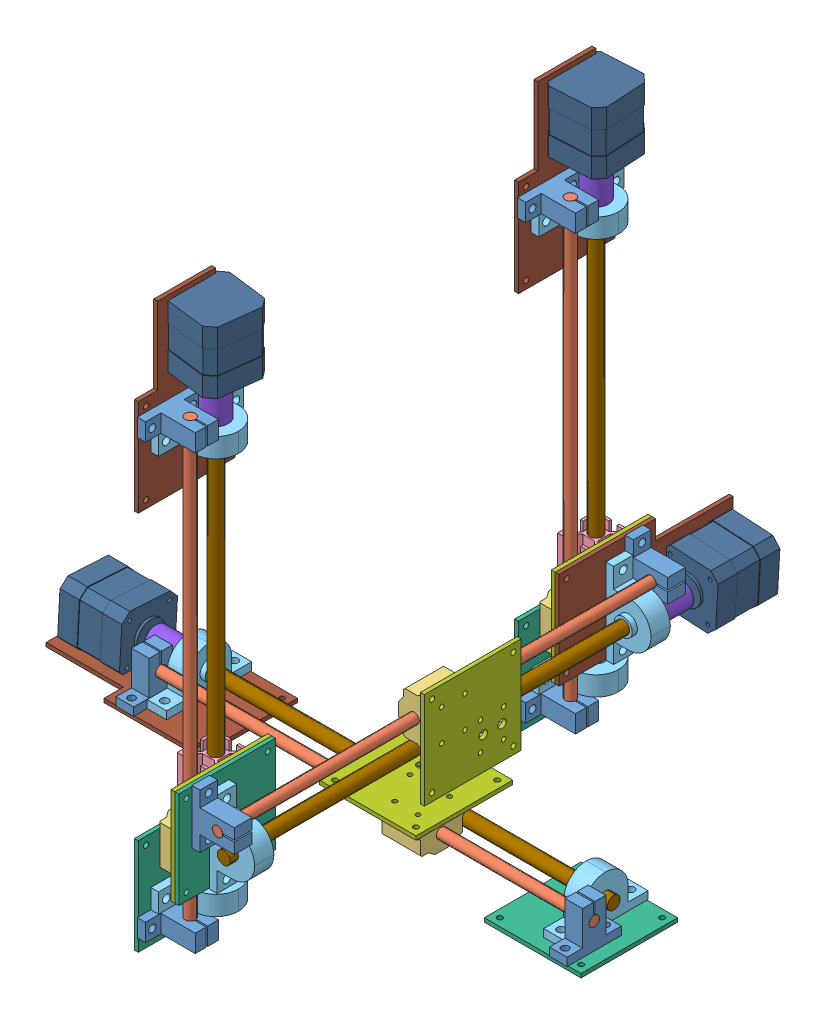
SolidWorks assembly PrinterAssembly, configuration Default. Lengths in mm.
Overall size (430 438.36 430).
60 component instances, 12 part files, 7 mates.
Components (placement in the parent):
- printer-1: printer [Default] at (379.3721 364.6591 311.6368) x (0 -1 0) z (0 0 1) size (442 48.34 82.75) (flexible)
  - M8_ Mil_Tutucu-4: M8_ Mil_Tutucu [Default] at (5.5091 -3.3233 99.5698) size (13.7 33 42)
  - M8_ Mil_Tutucu-5: M8_ Mil_Tutucu [Default] at (341.8091 -3.3233 99.5698) size (13.7 33 42)
  - M8_300_Mil-3: M8_300_Mil [Default] at (348.6591 16.7219 99.5698) x (0 0.969737 -0.244154) z (-1 0 0) size (8 8 350)
  - M8_Linear_Rulman-2: M8_Linear_Rulman [Default] at (296.9869 26.0544 99.5698) x (0 0 -1) z (-1 0 0) size (34.5 22.33 30)
  - Part4^printer-1: Part4^printer [Default] at origin (virtual)
  - 8mm_nut_profile-1: 8mm_nut_profile [Default] at (266.9869 14.1767 77.0698) x (0 0 1) z (-1 0 0) size (30 30 30)
  - UCP_10mm-1: UCP_10mm [Default] at (327.4591 -3.3233 77.0698) x (0 0 1) z (-1 0 0) size (66 35 19)
  - UCP_10mm-2: UCP_10mm [Default] at (19.8591 -3.3233 77.0698) x (0 0 -1) z (1 0 0) size (66 35 19)
  - Connection_Plate_Side-1: Connection_Plate_Side [Default] at (321.1591 -6.3233 82.3198) size (75 3 75)
  - Connection_Plate_Middle-1: Connection_Plate_Middle [Default] at (266.9869 29.1767 89.3198) size (75 3 75)
  - Kaplin_5-10mm-1: Kaplin_5-10mm [Default] at (11.3591 14.1767 77.0698) x (0 0.873711 0.486446) z (0 -0.486446 0.873711) size (19 25 19)
  - M10_Vidali_Mil-1: M10_Vidali_Mil [Default] at (1.3591 14.1767 77.0698) x (0 -0.999482 -0.03217) z (0 -0.03217 0.999482) size (10 340 10)
  - Nema17_stepper-1: Nema17_stepper [Default] at (-67.6409 14.1767 77.0698) x (0 -0.992266 -0.124131) z (0 -0.124131 0.992266) size (43.3 72 43.3)
  - Connection_Plate_Side_Stepper-1: Connection_Plate_Side_Stepper [Default] at (26.1591 -6.3233 82.3198) x (0 0 -1) z (1 0 0) size (75 3 135)
- printer-2: printer [Default] at (417.8721 15.3524 79.7975) x (0 0 1) z (0 1 0) size (442 45.72 82.75) (flexible)
  - M8_ Mil_Tutucu-4: M8_ Mil_Tutucu [Default] at (5.5091 -3.3233 99.5698) size (13.7 33 42)
  - M8_ Mil_Tutucu-5: M8_ Mil_Tutucu [Default] at (341.8091 -3.3233 99.5698) size (13.7 33 42)
  - M8_300_Mil-3: M8_300_Mil [Default] at (348.6591 16.7219 99.5698) x (0 0.969737 -0.244154) z (-1 0 0) size (8 8 350)
  - M8_Linear_Rulman-2: M8_Linear_Rulman [Default] at (196.1347 26.0544 99.5698) x (0 0 -1) z (-1 0 0) size (34.5 22.33 30)
  - Part4^printer-1: Part4^printer [Default] at origin (virtual)
  - 8mm_nut_profile-1: 8mm_nut_profile [Default] at (166.1347 14.1767 77.0698) x (0 0 1) z (-1 0 0) size (30 30 30)
  - UCP_10mm-1: UCP_10mm [Default] at (327.4591 -3.3233 77.0698) x (0 0 1) z (-1 0 0) size (66 35 19)
  - UCP_10mm-2: UCP_10mm [Default] at (19.8591 -3.3233 77.0698) x (0 0 -1) z (1 0 0) size (66 35 19)
  - Connection_Plate_Side-1: Connection_Plate_Side [Default] at (321.1591 -6.3233 82.3198) size (75 3 75)
  - Connection_Plate_Middle-1: Connection_Plate_Middle [Default] at (166.1347 29.1767 89.3198) size (75 3 75)
  - Kaplin_5-10mm-1: Kaplin_5-10mm [Default] at (11.3591 14.1767 77.0698) x (0 0.873711 0.486446) z (0 -0.486446 0.873711) size (19 25 19)
  - M10_Vidali_Mil-1: M10_Vidali_Mil [Default] at (1.3591 14.1767 77.0698) x (0 -0.999482 -0.03217) z (0 -0.03217 0.999482) size (10 340 10)
  - Nema17_stepper-1: Nema17_stepper [Default] at (-67.6409 14.1767 77.0698) x (0 -0.998341 0.05758) z (0 0.05758 0.998341) size (43.3 72 43.3)
  - Connection_Plate_Side_Stepper-1: Connection_Plate_Side_Stepper [Default] at (26.1591 -6.3233 82.3198) x (0 0 -1) z (1 0 0) size (75 3 135)
- printer-3: printer [Default] at (379.3721 364.6591 16.6368) x (0 -1 0) z (0 0 1) size (442 45.72 82.75) (flexible)
  - M8_ Mil_Tutucu-4: M8_ Mil_Tutucu [Default] at (5.5091 -3.3233 99.5698) size (13.7 33 42)
  - M8_ Mil_Tutucu-5: M8_ Mil_Tutucu [Default] at (341.8091 -3.3233 99.5698) size (13.7 33 42)
  - M8_300_Mil-3: M8_300_Mil [Default] at (348.6591 16.7219 99.5698) x (0 0.969737 -0.244154) z (-1 0 0) size (8 8 350)
  - M8_Linear_Rulman-2: M8_Linear_Rulman [Default] at (296.9869 26.0544 99.5698) x (0 0 -1) z (-1 0 0) size (34.5 22.33 30)
  - Part4^printer-1: Part4^printer [Default] at origin (virtual)
  - 8mm_nut_profile-1: 8mm_nut_profile [Default] at (266.9869 14.1767 77.0698) x (0 0 1) z (-1 0 0) size (30 30 30)
  - UCP_10mm-1: UCP_10mm [Default] at (327.4591 -3.3233 77.0698) x (0 0 1) z (-1 0 0) size (66 35 19)
  - UCP_10mm-2: UCP_10mm [Default] at (19.8591 -3.3233 77.0698) x (0 0 -1) z (1 0 0) size (66 35 19)
  - Connection_Plate_Side-1: Connection_Plate_Side [Default] at (321.1591 -6.3233 82.3198) size (75 3 75)
  - Connection_Plate_Middle-1: Connection_Plate_Middle [Default] at (266.9869 29.1767 89.3198) size (75 3 75)
  - Kaplin_5-10mm-1: Kaplin_5-10mm [Default] at (11.3591 14.1767 77.0698) x (0 0.873711 0.486446) z (0 -0.486446 0.873711) size (19 25 19)
  - M10_Vidali_Mil-1: M10_Vidali_Mil [Default] at (1.3591 14.1767 77.0698) x (0 -0.999482 -0.03217) z (0 -0.03217 0.999482) size (10 340 10)
  - Nema17_stepper-1: Nema17_stepper [Default] at (-67.6409 14.1767 77.0698) x (0 -0.998341 0.05758) z (0 0.05758 0.998341) size (43.3 72 43.3)
  - Connection_Plate_Side_Stepper-1: Connection_Plate_Side_Stepper [Default] at (26.1591 -6.3233 82.3198) x (0 0 -1) z (1 0 0) size (75 3 135)
- printer-4: printer [Default] at (200.3897 6.3233 151.1368) size (442 45.72 82.75) (flexible)
  - M8_ Mil_Tutucu-4: M8_ Mil_Tutucu [Default] at (5.5091 -3.3233 99.5698) size (13.7 33 42)
  - M8_ Mil_Tutucu-5: M8_ Mil_Tutucu [Default] at (341.8091 -3.3233 99.5698) size (13.7 33 42)
  - M8_300_Mil-3: M8_300_Mil [Default] at (348.6591 16.7219 99.5698) x (0 0.969737 -0.244154) z (-1 0 0) size (8 8 350)
  - M8_Linear_Rulman-2: M8_Linear_Rulman [Default] at (230.2024 26.0544 99.5698) x (0 0 -1) z (-1 0 0) size (34.5 22.33 30)
  - Part4^printer-1: Part4^printer [Default] at origin (virtual)
  - 8mm_nut_profile-1: 8mm_nut_profile [Default] at (200.2024 14.1767 77.0698) x (0 0 1) z (-1 0 0) size (30 30 30)
  - UCP_10mm-1: UCP_10mm [Default] at (327.4591 -3.3233 77.0698) x (0 0 1) z (-1 0 0) size (66 35 19)
  - UCP_10mm-2: UCP_10mm [Default] at (19.8591 -3.3233 77.0698) x (0 0 -1) z (1 0 0) size (66 35 19)
  - Connection_Plate_Side-1: Connection_Plate_Side [Default] at (321.1591 -6.3233 82.3198) size (75 3 75)
  - Connection_Plate_Middle-1: Connection_Plate_Middle [Default] at (200.2024 29.1767 89.3198) size (75 3 75)
  - Kaplin_5-10mm-1: Kaplin_5-10mm [Default] at (11.3591 14.1767 77.0698) x (0 0.873711 0.486446) z (0 -0.486446 0.873711) size (19 25 19)
  - M10_Vidali_Mil-1: M10_Vidali_Mil [Default] at (1.3591 14.1767 77.0698) x (0 -0.999482 -0.03217) z (0 -0.03217 0.999482) size (10 340 10)
  - Nema17_stepper-1: Nema17_stepper [Default] at (-67.6409 14.1767 77.0698) x (0 -0.998341 0.05758) z (0 0.05758 0.998341) size (43.3 72 43.3)
  - Connection_Plate_Side_Stepper-1: Connection_Plate_Side_Stepper [Default] at (26.1591 -6.3233 82.3198) x (0 0 -1) z (1 0 0) size (75 3 135)
Mates (geometry in assembly coordinates):
- Coincident1: coincident aligned: plane of printer-1/Connection_Plate_Side-1 through (373.0488 43.5 393.9566) normal (-1 0 0); plane of printer-3/Connection_Plate_Side-1 through (373.0488 43.5 98.9566) normal (-1 0 0)
- Coincident2: coincident aligned: plane of printer-1/Connection_Plate_Side-1 through (376.0488 6 431.4566) normal (0 -1 0); plane of printer-3/Connection_Plate_Side-1 through (376.0488 6 136.4566) normal (0 -1 0)
- Coincident3: coincident aligned: plane of printer-1/Connection_Plate_Middle-1 through (411.5488 135.1722 438.4566) normal (0 0 1); plane of printer-2/Connection_Plate_Side-1 through (414.5488 135.1722 438.4566) normal (0 0 1)
- Coincident4: coincident aligned: plane of printer-2/Connection_Plate_Side_Stepper-1 through (414.5488 75.1722 68.4566) normal (0 0 -1); plane of printer-3/Connection_Plate_Middle-1 through (411.5488 135.1722 68.4566) normal (0 0 -1)
- Coincident5: coincident anti-aligned: plane of printer-2/Connection_Plate_Side_Stepper-1 through (411.5488 97.6722 105.9566) normal (-1 0 0); plane of printer-3/Connection_Plate_Middle-1 through (411.5488 97.6722 105.9566) normal (1 0 0)
- Concentric1: concentric aligned: cylinder of printer-2/Connection_Plate_Side_Stepper-1 through (414.5488 129.1722 137.4566) axis (-1 0 0) radius 2; cylinder of printer-3/Connection_Plate_Middle-1 through (411.5488 129.1722 137.4566) axis (-1 0 0) radius 2
- Concentric2: concentric aligned: cylinder of printer-1/Connection_Plate_Middle-1 through (411.5488 129.1722 432.4566) axis (-1 0 0) radius 2; cylinder of printer-2/Connection_Plate_Side-1 through (414.5488 129.1722 432.4566) axis (-1 0 0) radius 2
